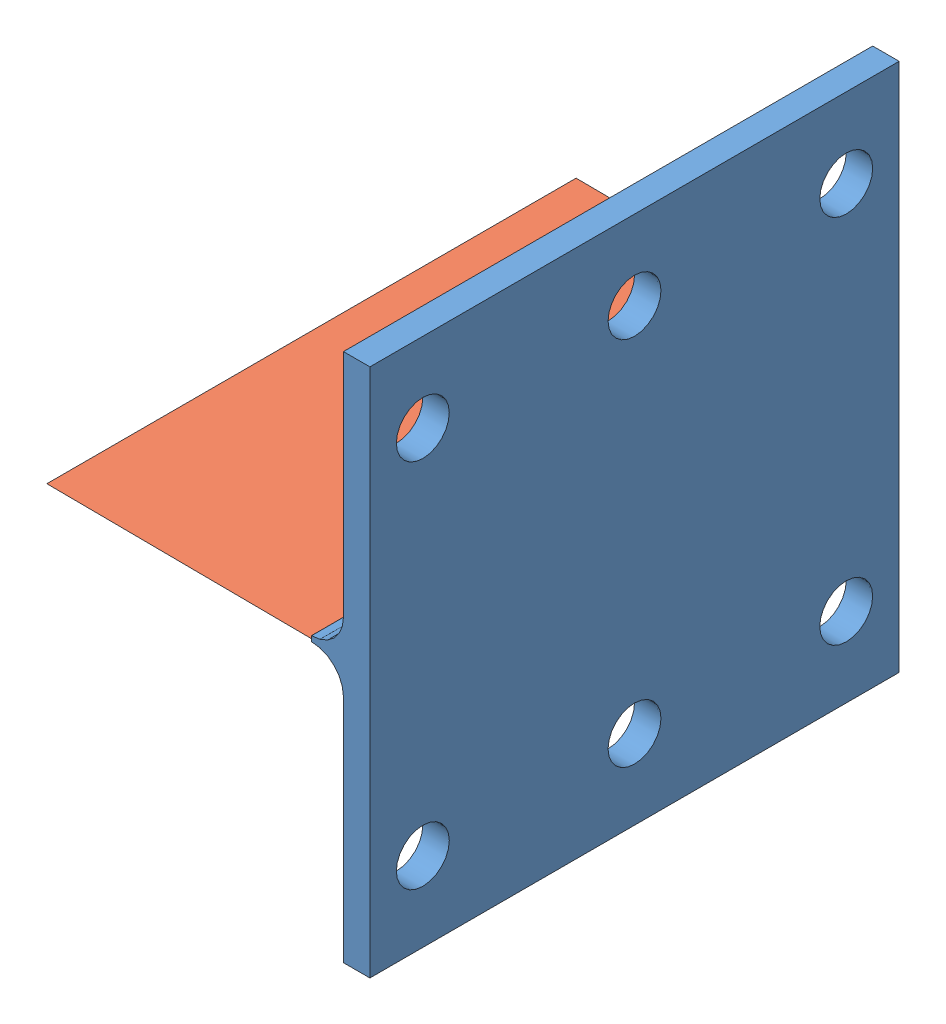
SolidWorks assembly mixedmesh-1, configuration Default. Lengths in mm.
Overall size (305.21 500 500).
2 component instances, 2 part files, 3 mates.
Components (placement in the parent):
- mixed-1-solid-3: mixed-1-solid [Default] at (73.8948 -32.753 -41.1471) size (55.2 500 500)
- mixed-1-shell-1: mixed-1-shell [Default] at (18.695 164.7765 458.8529) x (-0.999974 0.007198 0) z (0 0 -1) size (250 0 500)
Mates (geometry in assembly coordinates):
- Distance6: distance = 0 mm: plane of mixed-1-solid-3 through (18.695 167.2765 458.8529) normal (-1 0 0); line of mixed-1-shell-1 through (18.695 164.7765 458.8529) axis (0 0 -1)
- Distance7: distance = 2.5 mm: point of mixed-1-shell-1; point of mixed-1-solid-3
- Distance8: distance = 2.5 mm: line of mixed-1-solid-3 through (18.695 167.2765 458.8529) axis (0 0 -1); line of mixed-1-shell-1 through (18.695 164.7765 458.8529) axis (0 0 -1)
